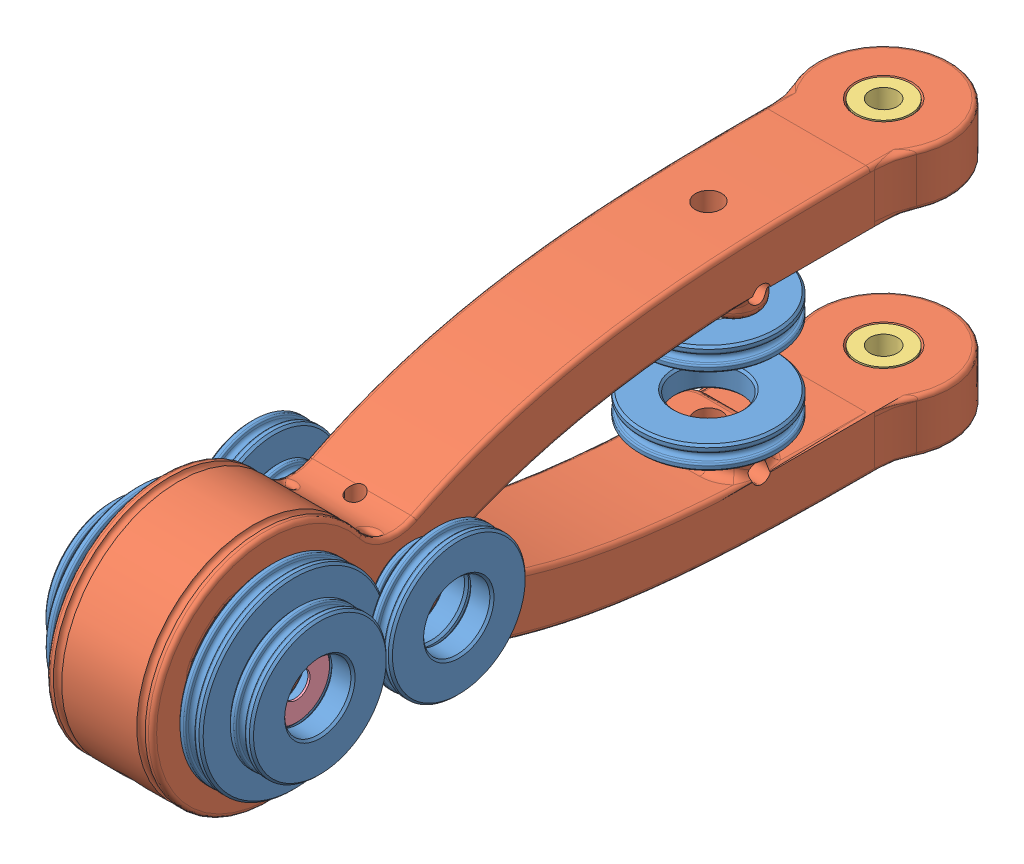
SolidWorks assembly Assem2^assembled_4dof_arm, configuration Default. Lengths in mm.
Overall size (24.87 40.24 102).
17 component instances, 4 part files, 22 mates.
Components (placement in the parent):
- Pulley_configurable-1: Pulley_configurable [p2_bearing] at (11.0482 0 0) x (0 0.579752 0.814793) z (0 -0.814793 0.579752) size (16.4 2.78 16.4)
- Pulley_configurable-4: Pulley_configurable [p1_bearing] at (8.0161 0 0) x (0 0.99994 0.01097) z (0 -0.01097 0.99994) size (22.4 2.78 22.4)
- Pulley_configurable-6: Pulley_configurable [p2_bearing] at (11.0482 0 -16.65) x (0 -0.778257 0.627946) z (0 -0.627946 -0.778257) size (16.4 2.78 16.4)
- Pulley_configurable-7: Pulley_configurable [p3_bearing] at (8.0161 0 -16.65) x (0 0.598722 0.800957) z (0 -0.800957 0.598722) size (10.4 2.78 10.4)
- joint2-1: joint2 [Default] x (-1 0 0) z (0 0 1) size (18.02 40.24 102)
- Pulley_configurable-10: Pulley_configurable [p2_bearing] at (0 -5.1069 -59) x (-0.966491 0 0.256701) z (0.256701 0 0.966491) size (16.4 2.78 16.4)
- Pulley_configurable-11: Pulley_configurable [p2_bearing] at (0 5.1069 -59) x (-0.966491 0 0.256701) z (0.256701 0 0.966491) size (16.4 2.78 16.4)
- 6377K490_ULTRA-LOW-FRICTION DRY-RUNNING SLEEVE BEARING-1: 6377K490_ULTRA-LOW-FRICTION DRY-RUNNING SLEEVE BEARING [6377K49] at (0 -12.8 -80) x (-1 0 -0.000919) z (0 1 0) size (6.38 6.38 6.35)
- 6377K490_ULTRA-LOW-FRICTION DRY-RUNNING SLEEVE BEARING-2: 6377K490_ULTRA-LOW-FRICTION DRY-RUNNING SLEEVE BEARING [6377K49] at (0 12.8 -80) x (1 0 -0.000919) z (0 -1 0) size (6.38 6.38 6.35)
- 10thouspacer_3125shaft-1: 10thouspacer_3125shaft [Default] at (9.4051 0 0) x (0 0.230055 0.973178) z (1 0 0) size (7.87 7.87 0.25)
- 10thouspacer_3125shaft-2: 10thouspacer_3125shaft [Default] at (6.373 0 0) x (0 0.98124 0.192789) z (1 0 0) size (7.87 7.87 0.25)
- Pulley_configurable-12: Pulley_configurable [p3_bearing] at (-8.0161 0 -16.65) x (0 0.598722 0.800957) z (0 0.800957 -0.598722) size (10.4 2.78 10.4)
- Pulley_configurable-13: Pulley_configurable [p1_bearing] at (-8.0161 0 0) x (0 0.99994 0.01097) z (0 0.01097 -0.99994) size (22.4 2.78 22.4)
- Pulley_configurable-14: Pulley_configurable [p2_bearing] at (-11.0482 0 0) x (0 0.579752 0.814793) z (0 0.814793 -0.579752) size (16.4 2.78 16.4)
- Pulley_configurable-15: Pulley_configurable [p2_bearing] at (-11.0482 0 -16.65) x (0 -0.778257 0.627946) z (0 0.627946 0.778257) size (16.4 2.78 16.4)
- 10thouspacer_3125shaft-3: 10thouspacer_3125shaft [Default] at (-9.6591 0 0) x (0 0.230055 0.973178) z (1 0 0) size (7.87 7.87 0.25)
- 10thouspacer_3125shaft-4: 10thouspacer_3125shaft [Default] at (-6.627 0 0) x (0 0.98124 0.192789) z (1 0 0) size (7.87 7.87 0.25)
Mates (geometry in assembly coordinates):
- Concentric18: concentric: cylinder of Pulley_configurable-1 through (11.0482 0 0) axis (1 0 0) radius 3.9688; cylinder of Pulley_configurable-4 through (8.0161 0 0) axis (1 0 0) radius 3.9688
- Concentric29: concentric: cylinder of Pulley_configurable-6 through (11.0482 0 -16.65) axis (1 0 0) radius 3.9688; cylinder of Pulley_configurable-7 through (8.0161 0 -16.65) axis (1 0 0) radius 3.9688
- Concentric35: concentric: cylinder of Pulley_configurable-6 through (11.0482 0 -16.65) axis (1 0 0) radius 3.9688; cylinder of joint2-1 through (-6.373 0 -16.65) axis (1 0 0) radius 1.5875
- Distance4: distance = 0.254 mm: plane of Pulley_configurable-10 through (0 -6.496 -59) normal (0 -1 0); plane of joint2-1 through (0 -6.75 0) normal (0 1 0)
- Distance5: distance = 0.254 mm: plane of Pulley_configurable-11 through (0 6.496 -59) normal (0 1 0); plane of joint2-1 through (0 6.75 0) normal (0 -1 0)
- Concentric59: concentric: cylinder of joint2-1 through (0 15.977 -59) axis (0 -1 0) radius 1.5875; cylinder of Pulley_configurable-10 through (0 -5.1069 -59) axis (0 1 0) radius 3.9688
- Concentric58: concentric: cylinder of Pulley_configurable-10 through (0 -5.1069 -59) axis (0 1 0) radius 3.9688; cylinder of Pulley_configurable-11 through (0 5.1069 -59) axis (0 1 0) radius 3.9688
- Concentric70: concentric: cylinder of joint2-1 through (0 -15.975 -80) axis (0 1 0) radius 3.175; cylinder of 6377K490_ULTRA-LOW-FRICTION DRY-RUNNING SLEEVE BEARING-1 through (0 -9.625 -80) axis (0 -1 0) radius 3.1877
- Coincident78: coincident: plane of joint2-1 through (0 -15.975 -80) normal (0 -1 0); plane of 6377K490_ULTRA-LOW-FRICTION DRY-RUNNING SLEEVE BEARING-1 through (0 -15.975 -80) normal (0 -1 0)
- Coincident77: coincident: plane of joint2-1 through (0 15.975 -80) normal (0 1 0); plane of 6377K490_ULTRA-LOW-FRICTION DRY-RUNNING SLEEVE BEARING-2 through (0 15.975 -80) normal (0 1 0)
- Concentric74: concentric: cylinder of 6377K490_ULTRA-LOW-FRICTION DRY-RUNNING SLEEVE BEARING-2 through (0 9.625 -80) axis (0 1 0) radius 3.1877; cylinder of 6377K490_ULTRA-LOW-FRICTION DRY-RUNNING SLEEVE BEARING-1 through (0 -9.625 -80) axis (0 -1 0) radius 3.1877
- Coincident79: coincident: plane of joint2-1 through (0 0 0) normal (0 0 1); plane of assembly through (0 0 0) normal (0 0 1)
- Coincident80: coincident: plane of joint2-1 through (0 0 0) normal (0 -1 0); plane of assembly through (0 0 0) normal (0 1 0)
- Coincident81: coincident: plane of joint2-1 through (0 0 0) normal (-1 0 0); plane of assembly through (0 0 0) normal (1 0 0)
- Coincident82: coincident: plane of Pulley_configurable-1 through (12.4373 0 0) normal (1 0 0); plane of Pulley_configurable-6 through (12.4373 0 -16.65) normal (1 0 0)
- Coincident83: coincident: plane of Pulley_configurable-4 through (9.4051 0 0) normal (1 0 0); plane of Pulley_configurable-7 through (9.4051 0 -16.65) normal (1 0 0)
- Concentric76: concentric: cylinder of joint2-1 through (-6.373 0 0) axis (1 0 0) radius 1.5875; cylinder of 10thouspacer_3125shaft-1 through (9.6591 0 0) axis (-1 0 0) radius 1.6002
- Coincident90: coincident: plane of joint2-1 through (6.373 0 0) normal (1 0 0); plane of 10thouspacer_3125shaft-2 through (6.373 0 0) normal (-1 0 0)
- Concentric77: concentric: cylinder of 10thouspacer_3125shaft-1 through (9.6591 0 0) axis (-1 0 0) radius 1.6002; cylinder of 10thouspacer_3125shaft-2 through (6.627 0 0) axis (-1 0 0) radius 1.6002
- Coincident91: coincident: plane of Pulley_configurable-4 through (6.627 0 0) normal (-1 0 0); plane of 10thouspacer_3125shaft-2 through (6.627 0 0) normal (1 0 0)
- Coincident92: coincident: plane of Pulley_configurable-4 through (9.4051 0 0) normal (1 0 0); plane of 10thouspacer_3125shaft-1 through (9.4051 0 0) normal (-1 0 0)
- Coincident93: coincident: plane of Pulley_configurable-1 through (9.6591 0 0) normal (-1 0 0); plane of 10thouspacer_3125shaft-1 through (9.6591 0 0) normal (1 0 0)
